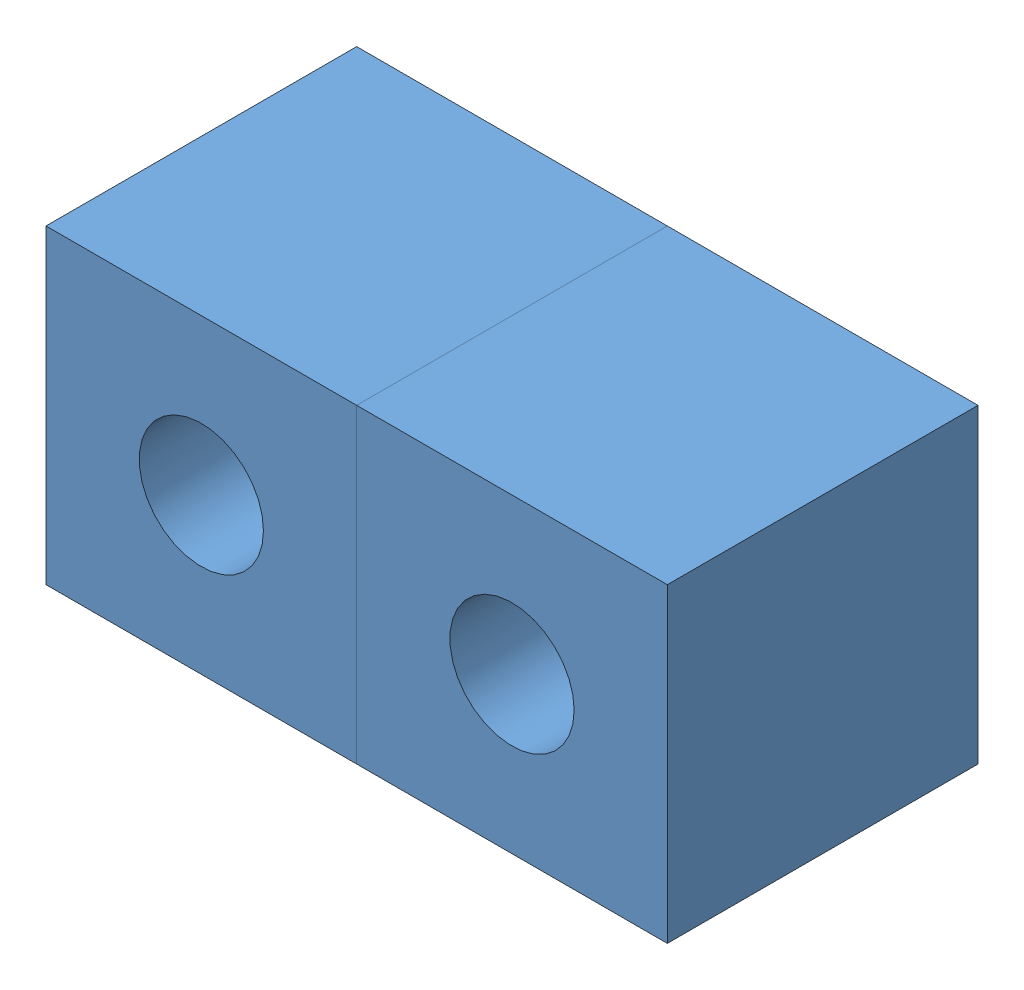
SolidWorks assembly Example, configuration Default. Lengths in mm.
Overall size (1524 762 762).
2 component instances, 1 part files, 6 mates.
Components (placement in the parent):
- example-1: example [Default] at (-381.0008 0 0) size (762 762 762)
- example-2: example [Default] at (381.0008 0 0) size (762 762 762)
Mates (geometry in assembly coordinates):
- Coincident1: coincident aligned: plane of example-1 through (0 -381.0008 381) normal (1 0 0)
- Coincident2: coincident aligned: plane of example-1 through (-381.0008 0 0) normal (0 0 1)
- Coincident4: coincident aligned: plane of example-1 through (-381.0008 0 0) normal (0 1 0)
- Coincident5: coincident anti-aligned: plane of example-2 through (0 -381.0008 381) normal (-1 0 0)
- Coincident6: coincident aligned: plane of example-2 through (381.0008 0 0) normal (0 0 1)
- Coincident7: coincident aligned: plane of example-2 through (381.0008 0 0) normal (0 1 0)
